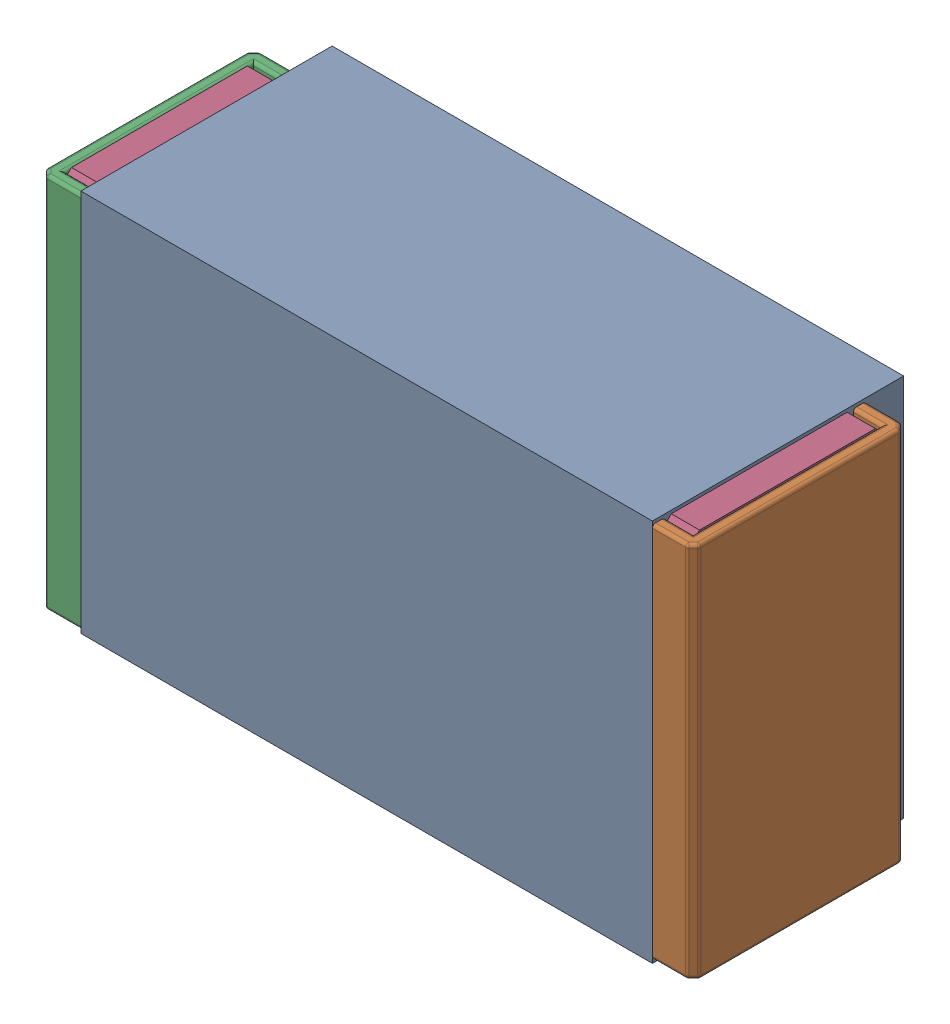
SolidWorks assembly R22, configuration Default. Lengths in mm.
Overall size (1.04 0.61 0.4).
3 component instances, 2 part files, 0 mates.
Components (placement in the parent):
- 1088880352-1: 1088880352 [Default] at (5.1 22.5 -2.044) size (0.91 0.61 0.4)
  - Extruded-28-1: Extruded-28 [Default] at origin size (0.91 0.61 0.4)
- R0402-1: R0402 [Default] at (5.1 22.5 -1.644) x (1 0 0) z (0 1 0) size (1.04 0.34 0.6)
